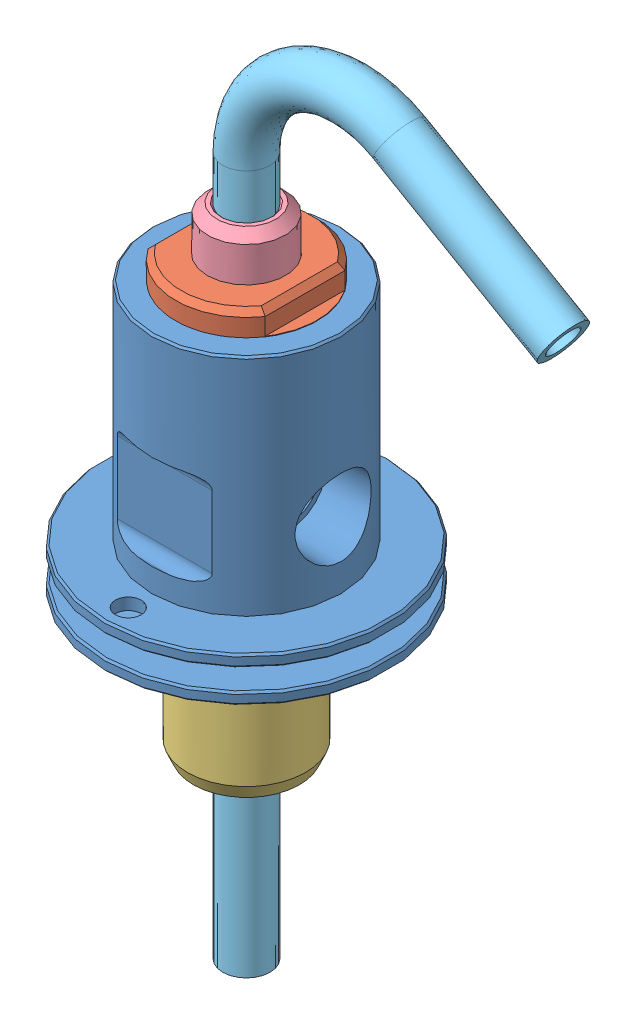
SolidWorks assembly PBS_500_FILLHD, configuration Default. Lengths in mm.
Overall size (64.92 110.77 41.52).
5 component instances, 5 part files, 7 mates.
Components (placement in the parent):
- PBS_510_M_FILLHD_BODY-2: PBS_510_M_FILLHD_BODY [Default] at origin size (38.1 55.16 38.1)
- PBS_520_M_FILLHD_NUT-2: PBS_520_M_FILLHD_NUT [Default] at (0 1.8548 0) size (19.05 13.46 19.05)
- PBS_530_X_FILLHD_SEAL-1: PBS_530_X_FILLHD_SEAL [Default] at (0 -36.1061 0) x (-0.837169 0 -0.546944) z (-0.546944 0 0.837169) size (30 19.05 30)
- PBS_515_M_FILLHD_INSERT-2: PBS_515_M_FILLHD_INSERT [Default] at (0 9.0392 0) x (0.997057 0 -0.076664) z (0.076664 0 0.997057) size (17.27 25.4 17.27)
- PBS_525_M_FILLHD_TUBE-1: PBS_525_M_FILLHD_TUBE [Default] at (0 -78.9673 0) x (-1 0 0) z (0 0 -1) size (47.33 110.77 6.35)
Mates (geometry in assembly coordinates):
- Coincident11: coincident aligned: plane of PBS_520_M_FILLHD_NUT-2 through (0 1.8548 0) normal (0 0 1); plane of assembly through (0 0 0) normal (0 0 1)
- Coincident12: coincident aligned: axis of PBS_510_M_FILLHD_BODY-2 through (0 0 0) axis (0 -1 0); axis of PBS_520_M_FILLHD_NUT-2 through (0 1.8548 0) axis (0 -1 0)
- Coincident13: coincident anti-aligned: plane of PBS_510_M_FILLHD_BODY-2 through (0 -36.1061 19.05) normal (0 -1 0); plane of PBS_530_X_FILLHD_SEAL-1 through (-12.5575 -36.1061 -8.2042) normal (0 1 0)
- Concentric1: concentric aligned: cylinder of PBS_510_M_FILLHD_BODY-2 through (0 0 0) axis (0 1 0) radius 6.35; cylinder of PBS_530_X_FILLHD_SEAL-1 through (0 -35.1536 0) axis (0 1 0) radius 7.9375
- Coincident14: coincident aligned: cone of PBS_520_M_FILLHD_NUT-2 through (0 -8.3052 0) axis (0 1 0); cone of PBS_515_M_FILLHD_INSERT-2 through (0 0.4045 0) axis (0 1 0)
- Concentric2: concentric anti-aligned: cylinder of PBS_515_M_FILLHD_INSERT-2 through (0 9.0392 0) axis (0 1 0) radius 5.207; cylinder of PBS_525_M_FILLHD_TUBE-1 through (0 14.9163 0) axis (0 -1 0) radius 3.175
- Coincident15: coincident anti-aligned: plane of PBS_525_M_FILLHD_TUBE-1 through (0 -78.9673 0) normal (0 0 -1); plane of assembly through (0 0 0) normal (0 0 1)
